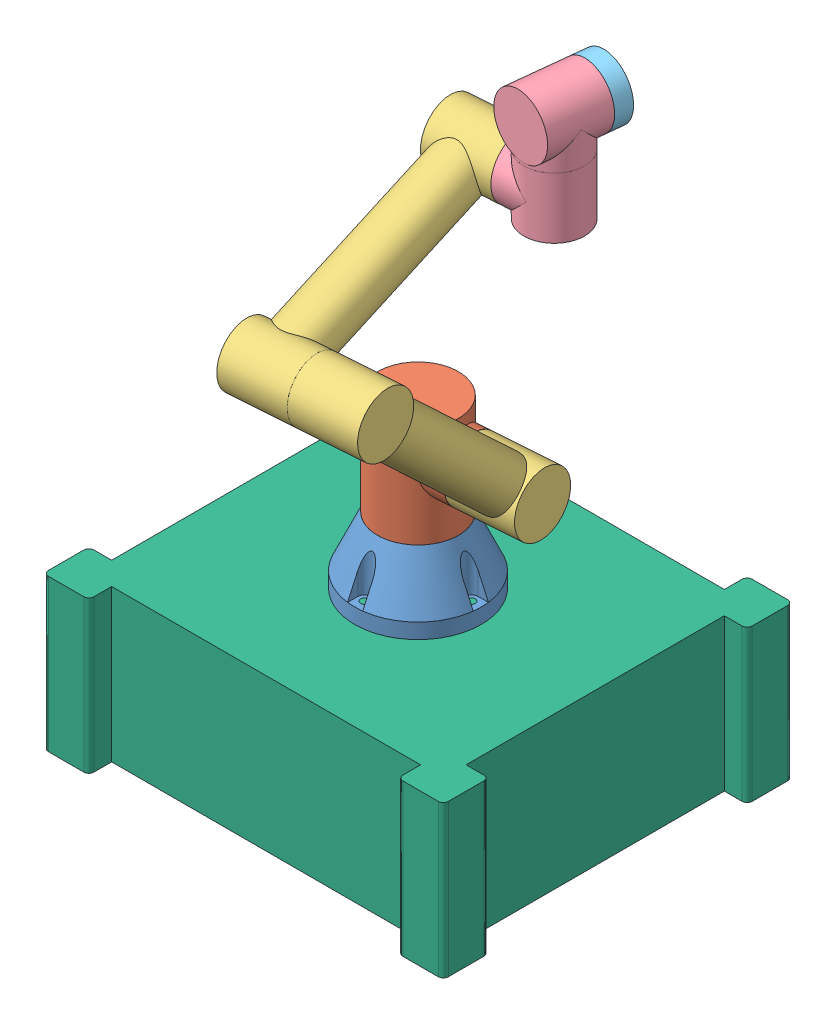
SolidWorks assembly Manipulator_model, configuration Default. Lengths in mm.
Overall size (395 600.81 379.36).
9 component instances, 6 part files, 3 mates.
Components (placement in the parent):
- armProto-1: armProto [Default] at (206.5629 277.8242 149.9649) x (-1 0 0) z (0 0 -1) size (192.39 450.81 312.75) (flexible)
  - armBase-1: armBase [Default] at origin size (125 80 125)
  - armLink1-1: armLink1 [Default] at (0 65 0) x (0.072345 0 0.99738) z (-0.99738 0 0.072345) size (80 100 105)
  - armLink2-1: armLink2 [Default] at (-87.2707 125 6.3302) x (-0.052698 0.685125 -0.726517) z (0.99738 0 -0.072345) size (290 60 80)
  - armLink2-2: armLink2 [Default] at (-24.5878 282.5788 -166.1945) x (0.068418 0.325013 0.943231) z (-0.99738 0 0.072345) size (290 60 80)
  - armLink3-1: armLink3 [Default] at (-78.6683 357.3318 55.8129) x (-0.072345 0 -0.99738) z (0 -1 0) size (60 62.5 75)
  - armLink3-2: armLink3 [Default] at (-78.6683 419.8318 55.8129) x (0.99412 0 0.108279) z (0.108279 0 -0.99412) size (60 62.5 75)
  - armEFMount-1: armEFMount [Default] at (-81.9167 419.8318 85.6365) x (0.993572 0.033224 0.10822) z (-0.108279 0 0.99412) size (60 60 17)
- Base-1: Base [Default] at (206.5629 277.8242 149.9649) size (395 165 345)
Mates (geometry in assembly coordinates):
- Concentric1: concentric anti-aligned: cylinder of armProto-1/armBase-1 through (206.5629 277.8242 97.4649) axis (0 1 0) radius 4; cylinder of Base-1 through (206.5629 292.8242 97.4649) axis (0 -1 0) radius 4
- Concentric2: concentric anti-aligned: cylinder of armProto-1/armBase-1 through (206.5629 277.8242 202.4649) axis (0 1 0) radius 4; cylinder of Base-1 through (206.5629 292.8242 202.4649) axis (0 -1 0) radius 4
- Coincident2: coincident anti-aligned: plane of armProto-1/armBase-1 through (206.5629 277.8242 149.9649) normal (0 -1 0); plane of Base-1 through (206.5629 277.8242 149.9649) normal (0 1 0)
